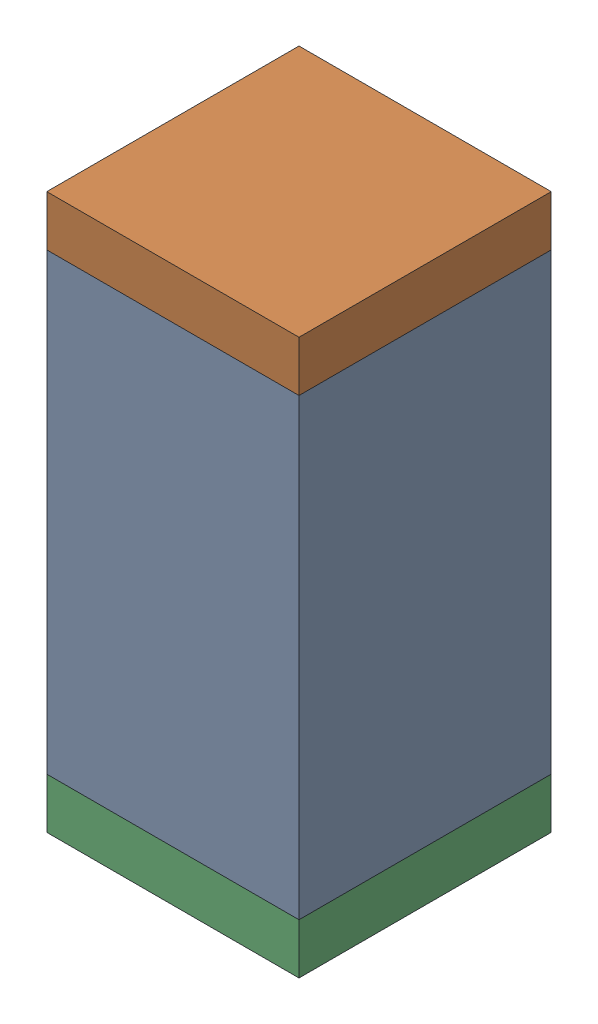
SolidWorks assembly R53, configuration Default. Lengths in mm.
Overall size (0.5 1.1 0.5).
6 component instances, 2 part files, 0 mates.
Components (placement in the parent):
- 791586336-1: 791586336 [Default] at (116.95 61.5 0) size (0.5 0.9 0.5)
  - Extruded_8-1: Extruded_8 [Default] at origin size (0.5 0.9 0.5)
- 810157360-1: 810157360 [Default] at (116.95 62 0) size (0.5 0.1 0.5)
  - Extruded_9-1: Extruded_9 [Default] at origin size (0.5 0.1 0.5)
- 810157360-2: 810157360 [Default] at (116.95 61 0) size (0.5 0.1 0.5)
  - Extruded_9-1: Extruded_9 [Default] at origin size (0.5 0.1 0.5)
